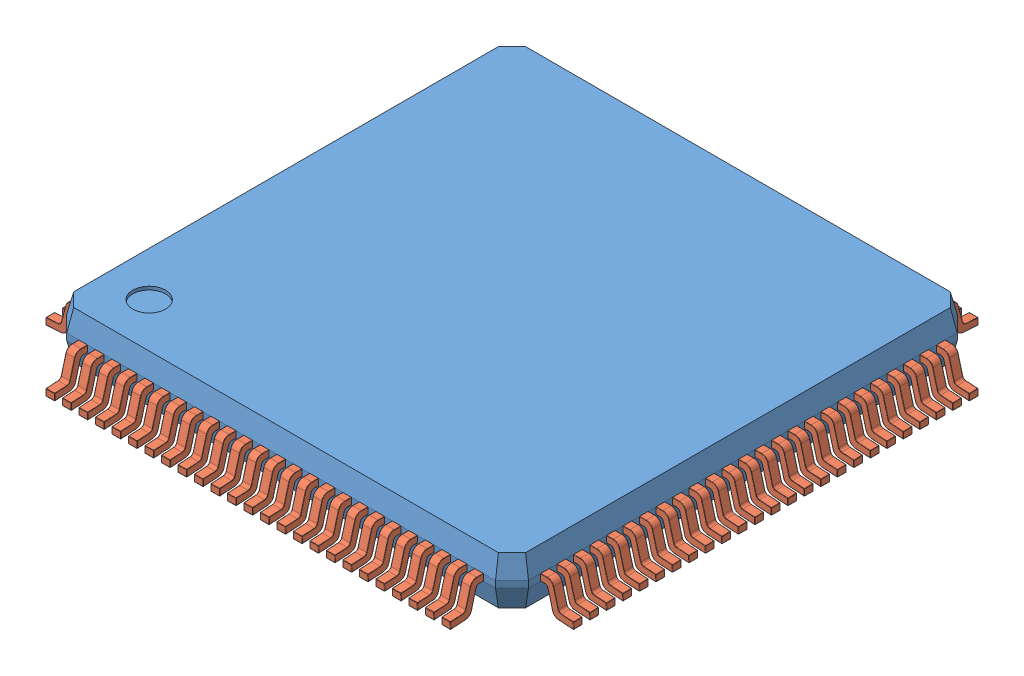
SolidWorks assembly User Library-LQFP100_Grid_0.5, configuration Default. Lengths in mm.
Overall size (16 1.6 16).
101 component instances, 2 part files, 0 mates.
Components (placement in the parent):
- User Library-LQFP100_Grid_0.5_LQFP100_Koerper_2-1: User Library-LQFP100_Grid_0.5_LQFP100_Koerper_2 [Default] at origin size (14 1.45 14)
- User Library-LQFP100_Grid_0.5_LQFP_PIN_2-1: User Library-LQFP100_Grid_0.5_LQFP_PIN_2 [Default] at (-6 0 8) size (0.27 0.97 1.5)
- User Library-LQFP100_Grid_0.5_LQFP_PIN_2-2: User Library-LQFP100_Grid_0.5_LQFP_PIN_2 [Default] at (-5.5 0 8) size (0.27 0.97 1.5)
- User Library-LQFP100_Grid_0.5_LQFP_PIN_2-3: User Library-LQFP100_Grid_0.5_LQFP_PIN_2 [Default] at (-5 0 8) size (0.27 0.97 1.5)
- User Library-LQFP100_Grid_0.5_LQFP_PIN_2-4: User Library-LQFP100_Grid_0.5_LQFP_PIN_2 [Default] at (-4.5 0 8) size (0.27 0.97 1.5)
- User Library-LQFP100_Grid_0.5_LQFP_PIN_2-5: User Library-LQFP100_Grid_0.5_LQFP_PIN_2 [Default] at (-4 0 8) size (0.27 0.97 1.5)
- User Library-LQFP100_Grid_0.5_LQFP_PIN_2-6: User Library-LQFP100_Grid_0.5_LQFP_PIN_2 [Default] at (-3.5 0 8) size (0.27 0.97 1.5)
- User Library-LQFP100_Grid_0.5_LQFP_PIN_2-7: User Library-LQFP100_Grid_0.5_LQFP_PIN_2 [Default] at (-3 0 8) size (0.27 0.97 1.5)
- User Library-LQFP100_Grid_0.5_LQFP_PIN_2-8: User Library-LQFP100_Grid_0.5_LQFP_PIN_2 [Default] at (-2.5 0 8) size (0.27 0.97 1.5)
- User Library-LQFP100_Grid_0.5_LQFP_PIN_2-9: User Library-LQFP100_Grid_0.5_LQFP_PIN_2 [Default] at (-2 0 8) size (0.27 0.97 1.5)
- User Library-LQFP100_Grid_0.5_LQFP_PIN_2-10: User Library-LQFP100_Grid_0.5_LQFP_PIN_2 [Default] at (-1.5 0 8) size (0.27 0.97 1.5)
- User Library-LQFP100_Grid_0.5_LQFP_PIN_2-11: User Library-LQFP100_Grid_0.5_LQFP_PIN_2 [Default] at (-1 0 8) size (0.27 0.97 1.5)
- User Library-LQFP100_Grid_0.5_LQFP_PIN_2-12: User Library-LQFP100_Grid_0.5_LQFP_PIN_2 [Default] at (-0.5 0 8) size (0.27 0.97 1.5)
- User Library-LQFP100_Grid_0.5_LQFP_PIN_2-13: User Library-LQFP100_Grid_0.5_LQFP_PIN_2 [Default] at (0 0 8) size (0.27 0.97 1.5)
- User Library-LQFP100_Grid_0.5_LQFP_PIN_2-14: User Library-LQFP100_Grid_0.5_LQFP_PIN_2 [Default] at (0.5 0 8) size (0.27 0.97 1.5)
- User Library-LQFP100_Grid_0.5_LQFP_PIN_2-15: User Library-LQFP100_Grid_0.5_LQFP_PIN_2 [Default] at (1 0 8) size (0.27 0.97 1.5)
- User Library-LQFP100_Grid_0.5_LQFP_PIN_2-16: User Library-LQFP100_Grid_0.5_LQFP_PIN_2 [Default] at (1.5 0 8) size (0.27 0.97 1.5)
- User Library-LQFP100_Grid_0.5_LQFP_PIN_2-17: User Library-LQFP100_Grid_0.5_LQFP_PIN_2 [Default] at (2 0 8) size (0.27 0.97 1.5)
- User Library-LQFP100_Grid_0.5_LQFP_PIN_2-18: User Library-LQFP100_Grid_0.5_LQFP_PIN_2 [Default] at (2.5 0 8) size (0.27 0.97 1.5)
- User Library-LQFP100_Grid_0.5_LQFP_PIN_2-19: User Library-LQFP100_Grid_0.5_LQFP_PIN_2 [Default] at (3 0 8) size (0.27 0.97 1.5)
- User Library-LQFP100_Grid_0.5_LQFP_PIN_2-20: User Library-LQFP100_Grid_0.5_LQFP_PIN_2 [Default] at (3.5 0 8) size (0.27 0.97 1.5)
- User Library-LQFP100_Grid_0.5_LQFP_PIN_2-21: User Library-LQFP100_Grid_0.5_LQFP_PIN_2 [Default] at (4 0 8) size (0.27 0.97 1.5)
- User Library-LQFP100_Grid_0.5_LQFP_PIN_2-22: User Library-LQFP100_Grid_0.5_LQFP_PIN_2 [Default] at (4.5 0 8) size (0.27 0.97 1.5)
- User Library-LQFP100_Grid_0.5_LQFP_PIN_2-23: User Library-LQFP100_Grid_0.5_LQFP_PIN_2 [Default] at (5 0 8) size (0.27 0.97 1.5)
- User Library-LQFP100_Grid_0.5_LQFP_PIN_2-24: User Library-LQFP100_Grid_0.5_LQFP_PIN_2 [Default] at (5.5 0 8) size (0.27 0.97 1.5)
- User Library-LQFP100_Grid_0.5_LQFP_PIN_2-25: User Library-LQFP100_Grid_0.5_LQFP_PIN_2 [Default] at (6 0 8) size (0.27 0.97 1.5)
- User Library-LQFP100_Grid_0.5_LQFP_PIN_2-26: User Library-LQFP100_Grid_0.5_LQFP_PIN_2 [Default] at (8 0 6) x (0 0 -1) z (1 0 0) size (0.27 0.97 1.5)
- User Library-LQFP100_Grid_0.5_LQFP_PIN_2-27: User Library-LQFP100_Grid_0.5_LQFP_PIN_2 [Default] at (8 0 5.5) x (0 0 -1) z (1 0 0) size (0.27 0.97 1.5)
- User Library-LQFP100_Grid_0.5_LQFP_PIN_2-28: User Library-LQFP100_Grid_0.5_LQFP_PIN_2 [Default] at (8 0 5) x (0 0 -1) z (1 0 0) size (0.27 0.97 1.5)
- User Library-LQFP100_Grid_0.5_LQFP_PIN_2-29: User Library-LQFP100_Grid_0.5_LQFP_PIN_2 [Default] at (8 0 4.5) x (0 0 -1) z (1 0 0) size (0.27 0.97 1.5)
- User Library-LQFP100_Grid_0.5_LQFP_PIN_2-30: User Library-LQFP100_Grid_0.5_LQFP_PIN_2 [Default] at (8 0 4) x (0 0 -1) z (1 0 0) size (0.27 0.97 1.5)
- User Library-LQFP100_Grid_0.5_LQFP_PIN_2-31: User Library-LQFP100_Grid_0.5_LQFP_PIN_2 [Default] at (8 0 3.5) x (0 0 -1) z (1 0 0) size (0.27 0.97 1.5)
- User Library-LQFP100_Grid_0.5_LQFP_PIN_2-32: User Library-LQFP100_Grid_0.5_LQFP_PIN_2 [Default] at (8 0 3) x (0 0 -1) z (1 0 0) size (0.27 0.97 1.5)
- User Library-LQFP100_Grid_0.5_LQFP_PIN_2-33: User Library-LQFP100_Grid_0.5_LQFP_PIN_2 [Default] at (8 0 2.5) x (0 0 -1) z (1 0 0) size (0.27 0.97 1.5)
- User Library-LQFP100_Grid_0.5_LQFP_PIN_2-34: User Library-LQFP100_Grid_0.5_LQFP_PIN_2 [Default] at (8 0 2) x (0 0 -1) z (1 0 0) size (0.27 0.97 1.5)
- User Library-LQFP100_Grid_0.5_LQFP_PIN_2-35: User Library-LQFP100_Grid_0.5_LQFP_PIN_2 [Default] at (8 0 1.5) x (0 0 -1) z (1 0 0) size (0.27 0.97 1.5)
- User Library-LQFP100_Grid_0.5_LQFP_PIN_2-36: User Library-LQFP100_Grid_0.5_LQFP_PIN_2 [Default] at (8 0 1) x (0 0 -1) z (1 0 0) size (0.27 0.97 1.5)
- User Library-LQFP100_Grid_0.5_LQFP_PIN_2-37: User Library-LQFP100_Grid_0.5_LQFP_PIN_2 [Default] at (8 0 0.5) x (0 0 -1) z (1 0 0) size (0.27 0.97 1.5)
- User Library-LQFP100_Grid_0.5_LQFP_PIN_2-38: User Library-LQFP100_Grid_0.5_LQFP_PIN_2 [Default] at (8 0 0) x (0 0 -1) z (1 0 0) size (0.27 0.97 1.5)
- User Library-LQFP100_Grid_0.5_LQFP_PIN_2-39: User Library-LQFP100_Grid_0.5_LQFP_PIN_2 [Default] at (8 0 -0.5) x (0 0 -1) z (1 0 0) size (0.27 0.97 1.5)
- User Library-LQFP100_Grid_0.5_LQFP_PIN_2-40: User Library-LQFP100_Grid_0.5_LQFP_PIN_2 [Default] at (8 0 -1) x (0 0 -1) z (1 0 0) size (0.27 0.97 1.5)
- User Library-LQFP100_Grid_0.5_LQFP_PIN_2-41: User Library-LQFP100_Grid_0.5_LQFP_PIN_2 [Default] at (8 0 -1.5) x (0 0 -1) z (1 0 0) size (0.27 0.97 1.5)
- User Library-LQFP100_Grid_0.5_LQFP_PIN_2-42: User Library-LQFP100_Grid_0.5_LQFP_PIN_2 [Default] at (8 0 -2) x (0 0 -1) z (1 0 0) size (0.27 0.97 1.5)
- User Library-LQFP100_Grid_0.5_LQFP_PIN_2-43: User Library-LQFP100_Grid_0.5_LQFP_PIN_2 [Default] at (8 0 -2.5) x (0 0 -1) z (1 0 0) size (0.27 0.97 1.5)
- User Library-LQFP100_Grid_0.5_LQFP_PIN_2-44: User Library-LQFP100_Grid_0.5_LQFP_PIN_2 [Default] at (8 0 -3) x (0 0 -1) z (1 0 0) size (0.27 0.97 1.5)
- User Library-LQFP100_Grid_0.5_LQFP_PIN_2-45: User Library-LQFP100_Grid_0.5_LQFP_PIN_2 [Default] at (8 0 -3.5) x (0 0 -1) z (1 0 0) size (0.27 0.97 1.5)
- User Library-LQFP100_Grid_0.5_LQFP_PIN_2-46: User Library-LQFP100_Grid_0.5_LQFP_PIN_2 [Default] at (8 0 -4) x (0 0 -1) z (1 0 0) size (0.27 0.97 1.5)
- User Library-LQFP100_Grid_0.5_LQFP_PIN_2-47: User Library-LQFP100_Grid_0.5_LQFP_PIN_2 [Default] at (8 0 -4.5) x (0 0 -1) z (1 0 0) size (0.27 0.97 1.5)
- User Library-LQFP100_Grid_0.5_LQFP_PIN_2-48: User Library-LQFP100_Grid_0.5_LQFP_PIN_2 [Default] at (8 0 -5) x (0 0 -1) z (1 0 0) size (0.27 0.97 1.5)
- User Library-LQFP100_Grid_0.5_LQFP_PIN_2-49: User Library-LQFP100_Grid_0.5_LQFP_PIN_2 [Default] at (8 0 -5.5) x (0 0 -1) z (1 0 0) size (0.27 0.97 1.5)
- User Library-LQFP100_Grid_0.5_LQFP_PIN_2-50: User Library-LQFP100_Grid_0.5_LQFP_PIN_2 [Default] at (8 0 -6) x (0 0 -1) z (1 0 0) size (0.27 0.97 1.5)
- User Library-LQFP100_Grid_0.5_LQFP_PIN_2-51: User Library-LQFP100_Grid_0.5_LQFP_PIN_2 [Default] at (6 0 -8) x (-1 0 0) z (0 0 -1) size (0.27 0.97 1.5)
- User Library-LQFP100_Grid_0.5_LQFP_PIN_2-52: User Library-LQFP100_Grid_0.5_LQFP_PIN_2 [Default] at (5.5 0 -8) x (-1 0 0) z (0 0 -1) size (0.27 0.97 1.5)
- User Library-LQFP100_Grid_0.5_LQFP_PIN_2-53: User Library-LQFP100_Grid_0.5_LQFP_PIN_2 [Default] at (5 0 -8) x (-1 0 0) z (0 0 -1) size (0.27 0.97 1.5)
- User Library-LQFP100_Grid_0.5_LQFP_PIN_2-54: User Library-LQFP100_Grid_0.5_LQFP_PIN_2 [Default] at (4.5 0 -8) x (-1 0 0) z (0 0 -1) size (0.27 0.97 1.5)
- User Library-LQFP100_Grid_0.5_LQFP_PIN_2-55: User Library-LQFP100_Grid_0.5_LQFP_PIN_2 [Default] at (4 0 -8) x (-1 0 0) z (0 0 -1) size (0.27 0.97 1.5)
- User Library-LQFP100_Grid_0.5_LQFP_PIN_2-56: User Library-LQFP100_Grid_0.5_LQFP_PIN_2 [Default] at (3.5 0 -8) x (-1 0 0) z (0 0 -1) size (0.27 0.97 1.5)
- User Library-LQFP100_Grid_0.5_LQFP_PIN_2-57: User Library-LQFP100_Grid_0.5_LQFP_PIN_2 [Default] at (3 0 -8) x (-1 0 0) z (0 0 -1) size (0.27 0.97 1.5)
- User Library-LQFP100_Grid_0.5_LQFP_PIN_2-58: User Library-LQFP100_Grid_0.5_LQFP_PIN_2 [Default] at (2.5 0 -8) x (-1 0 0) z (0 0 -1) size (0.27 0.97 1.5)
- User Library-LQFP100_Grid_0.5_LQFP_PIN_2-59: User Library-LQFP100_Grid_0.5_LQFP_PIN_2 [Default] at (2 0 -8) x (-1 0 0) z (0 0 -1) size (0.27 0.97 1.5)
- User Library-LQFP100_Grid_0.5_LQFP_PIN_2-60: User Library-LQFP100_Grid_0.5_LQFP_PIN_2 [Default] at (1.5 0 -8) x (-1 0 0) z (0 0 -1) size (0.27 0.97 1.5)
- User Library-LQFP100_Grid_0.5_LQFP_PIN_2-61: User Library-LQFP100_Grid_0.5_LQFP_PIN_2 [Default] at (1 0 -8) x (-1 0 0) z (0 0 -1) size (0.27 0.97 1.5)
- User Library-LQFP100_Grid_0.5_LQFP_PIN_2-62: User Library-LQFP100_Grid_0.5_LQFP_PIN_2 [Default] at (0.5 0 -8) x (-1 0 0) z (0 0 -1) size (0.27 0.97 1.5)
- User Library-LQFP100_Grid_0.5_LQFP_PIN_2-63: User Library-LQFP100_Grid_0.5_LQFP_PIN_2 [Default] at (0 0 -8) x (-1 0 0) z (0 0 -1) size (0.27 0.97 1.5)
- User Library-LQFP100_Grid_0.5_LQFP_PIN_2-64: User Library-LQFP100_Grid_0.5_LQFP_PIN_2 [Default] at (-0.5 0 -8) x (-1 0 0) z (0 0 -1) size (0.27 0.97 1.5)
- User Library-LQFP100_Grid_0.5_LQFP_PIN_2-65: User Library-LQFP100_Grid_0.5_LQFP_PIN_2 [Default] at (-1 0 -8) x (-1 0 0) z (0 0 -1) size (0.27 0.97 1.5)
- User Library-LQFP100_Grid_0.5_LQFP_PIN_2-66: User Library-LQFP100_Grid_0.5_LQFP_PIN_2 [Default] at (-1.5 0 -8) x (-1 0 0) z (0 0 -1) size (0.27 0.97 1.5)
- User Library-LQFP100_Grid_0.5_LQFP_PIN_2-67: User Library-LQFP100_Grid_0.5_LQFP_PIN_2 [Default] at (-2 0 -8) x (-1 0 0) z (0 0 -1) size (0.27 0.97 1.5)
- User Library-LQFP100_Grid_0.5_LQFP_PIN_2-68: User Library-LQFP100_Grid_0.5_LQFP_PIN_2 [Default] at (-2.5 0 -8) x (-1 0 0) z (0 0 -1) size (0.27 0.97 1.5)
- User Library-LQFP100_Grid_0.5_LQFP_PIN_2-69: User Library-LQFP100_Grid_0.5_LQFP_PIN_2 [Default] at (-3 0 -8) x (-1 0 0) z (0 0 -1) size (0.27 0.97 1.5)
- User Library-LQFP100_Grid_0.5_LQFP_PIN_2-70: User Library-LQFP100_Grid_0.5_LQFP_PIN_2 [Default] at (-3.5 0 -8) x (-1 0 0) z (0 0 -1) size (0.27 0.97 1.5)
- User Library-LQFP100_Grid_0.5_LQFP_PIN_2-71: User Library-LQFP100_Grid_0.5_LQFP_PIN_2 [Default] at (-4 0 -8) x (-1 0 0) z (0 0 -1) size (0.27 0.97 1.5)
- User Library-LQFP100_Grid_0.5_LQFP_PIN_2-72: User Library-LQFP100_Grid_0.5_LQFP_PIN_2 [Default] at (-4.5 0 -8) x (-1 0 0) z (0 0 -1) size (0.27 0.97 1.5)
- User Library-LQFP100_Grid_0.5_LQFP_PIN_2-73: User Library-LQFP100_Grid_0.5_LQFP_PIN_2 [Default] at (-5 0 -8) x (-1 0 0) z (0 0 -1) size (0.27 0.97 1.5)
- User Library-LQFP100_Grid_0.5_LQFP_PIN_2-74: User Library-LQFP100_Grid_0.5_LQFP_PIN_2 [Default] at (-5.5 0 -8) x (-1 0 0) z (0 0 -1) size (0.27 0.97 1.5)
- User Library-LQFP100_Grid_0.5_LQFP_PIN_2-75: User Library-LQFP100_Grid_0.5_LQFP_PIN_2 [Default] at (-6 0 -8) x (-1 0 0) z (0 0 -1) size (0.27 0.97 1.5)
- User Library-LQFP100_Grid_0.5_LQFP_PIN_2-76: User Library-LQFP100_Grid_0.5_LQFP_PIN_2 [Default] at (-8 0 -6) x (0 0 1) z (-1 0 0) size (0.27 0.97 1.5)
- User Library-LQFP100_Grid_0.5_LQFP_PIN_2-77: User Library-LQFP100_Grid_0.5_LQFP_PIN_2 [Default] at (-8 0 -5.5) x (0 0 1) z (-1 0 0) size (0.27 0.97 1.5)
- User Library-LQFP100_Grid_0.5_LQFP_PIN_2-78: User Library-LQFP100_Grid_0.5_LQFP_PIN_2 [Default] at (-8 0 -5) x (0 0 1) z (-1 0 0) size (0.27 0.97 1.5)
- User Library-LQFP100_Grid_0.5_LQFP_PIN_2-79: User Library-LQFP100_Grid_0.5_LQFP_PIN_2 [Default] at (-8 0 -4.5) x (0 0 1) z (-1 0 0) size (0.27 0.97 1.5)
- User Library-LQFP100_Grid_0.5_LQFP_PIN_2-80: User Library-LQFP100_Grid_0.5_LQFP_PIN_2 [Default] at (-8 0 -4) x (0 0 1) z (-1 0 0) size (0.27 0.97 1.5)
- User Library-LQFP100_Grid_0.5_LQFP_PIN_2-81: User Library-LQFP100_Grid_0.5_LQFP_PIN_2 [Default] at (-8 0 -3.5) x (0 0 1) z (-1 0 0) size (0.27 0.97 1.5)
- User Library-LQFP100_Grid_0.5_LQFP_PIN_2-82: User Library-LQFP100_Grid_0.5_LQFP_PIN_2 [Default] at (-8 0 -3) x (0 0 1) z (-1 0 0) size (0.27 0.97 1.5)
- User Library-LQFP100_Grid_0.5_LQFP_PIN_2-83: User Library-LQFP100_Grid_0.5_LQFP_PIN_2 [Default] at (-8 0 -2.5) x (0 0 1) z (-1 0 0) size (0.27 0.97 1.5)
- User Library-LQFP100_Grid_0.5_LQFP_PIN_2-84: User Library-LQFP100_Grid_0.5_LQFP_PIN_2 [Default] at (-8 0 -2) x (0 0 1) z (-1 0 0) size (0.27 0.97 1.5)
- User Library-LQFP100_Grid_0.5_LQFP_PIN_2-85: User Library-LQFP100_Grid_0.5_LQFP_PIN_2 [Default] at (-8 0 -1.5) x (0 0 1) z (-1 0 0) size (0.27 0.97 1.5)
- User Library-LQFP100_Grid_0.5_LQFP_PIN_2-86: User Library-LQFP100_Grid_0.5_LQFP_PIN_2 [Default] at (-8 0 -1) x (0 0 1) z (-1 0 0) size (0.27 0.97 1.5)
- User Library-LQFP100_Grid_0.5_LQFP_PIN_2-87: User Library-LQFP100_Grid_0.5_LQFP_PIN_2 [Default] at (-8 0 -0.5) x (0 0 1) z (-1 0 0) size (0.27 0.97 1.5)
- User Library-LQFP100_Grid_0.5_LQFP_PIN_2-88: User Library-LQFP100_Grid_0.5_LQFP_PIN_2 [Default] at (-8 0 0) x (0 0 1) z (-1 0 0) size (0.27 0.97 1.5)
- User Library-LQFP100_Grid_0.5_LQFP_PIN_2-89: User Library-LQFP100_Grid_0.5_LQFP_PIN_2 [Default] at (-8 0 0.5) x (0 0 1) z (-1 0 0) size (0.27 0.97 1.5)
- User Library-LQFP100_Grid_0.5_LQFP_PIN_2-90: User Library-LQFP100_Grid_0.5_LQFP_PIN_2 [Default] at (-8 0 1) x (0 0 1) z (-1 0 0) size (0.27 0.97 1.5)
- User Library-LQFP100_Grid_0.5_LQFP_PIN_2-91: User Library-LQFP100_Grid_0.5_LQFP_PIN_2 [Default] at (-8 0 1.5) x (0 0 1) z (-1 0 0) size (0.27 0.97 1.5)
- User Library-LQFP100_Grid_0.5_LQFP_PIN_2-92: User Library-LQFP100_Grid_0.5_LQFP_PIN_2 [Default] at (-8 0 2) x (0 0 1) z (-1 0 0) size (0.27 0.97 1.5)
- User Library-LQFP100_Grid_0.5_LQFP_PIN_2-93: User Library-LQFP100_Grid_0.5_LQFP_PIN_2 [Default] at (-8 0 2.5) x (0 0 1) z (-1 0 0) size (0.27 0.97 1.5)
- User Library-LQFP100_Grid_0.5_LQFP_PIN_2-94: User Library-LQFP100_Grid_0.5_LQFP_PIN_2 [Default] at (-8 0 3) x (0 0 1) z (-1 0 0) size (0.27 0.97 1.5)
- User Library-LQFP100_Grid_0.5_LQFP_PIN_2-95: User Library-LQFP100_Grid_0.5_LQFP_PIN_2 [Default] at (-8 0 3.5) x (0 0 1) z (-1 0 0) size (0.27 0.97 1.5)
- User Library-LQFP100_Grid_0.5_LQFP_PIN_2-96: User Library-LQFP100_Grid_0.5_LQFP_PIN_2 [Default] at (-8 0 4) x (0 0 1) z (-1 0 0) size (0.27 0.97 1.5)
- User Library-LQFP100_Grid_0.5_LQFP_PIN_2-97: User Library-LQFP100_Grid_0.5_LQFP_PIN_2 [Default] at (-8 0 4.5) x (0 0 1) z (-1 0 0) size (0.27 0.97 1.5)
- User Library-LQFP100_Grid_0.5_LQFP_PIN_2-98: User Library-LQFP100_Grid_0.5_LQFP_PIN_2 [Default] at (-8 0 5) x (0 0 1) z (-1 0 0) size (0.27 0.97 1.5)
- User Library-LQFP100_Grid_0.5_LQFP_PIN_2-99: User Library-LQFP100_Grid_0.5_LQFP_PIN_2 [Default] at (-8 0 5.5) x (0 0 1) z (-1 0 0) size (0.27 0.97 1.5)
- User Library-LQFP100_Grid_0.5_LQFP_PIN_2-100: User Library-LQFP100_Grid_0.5_LQFP_PIN_2 [Default] at (-8 0 6) x (0 0 1) z (-1 0 0) size (0.27 0.97 1.5)
